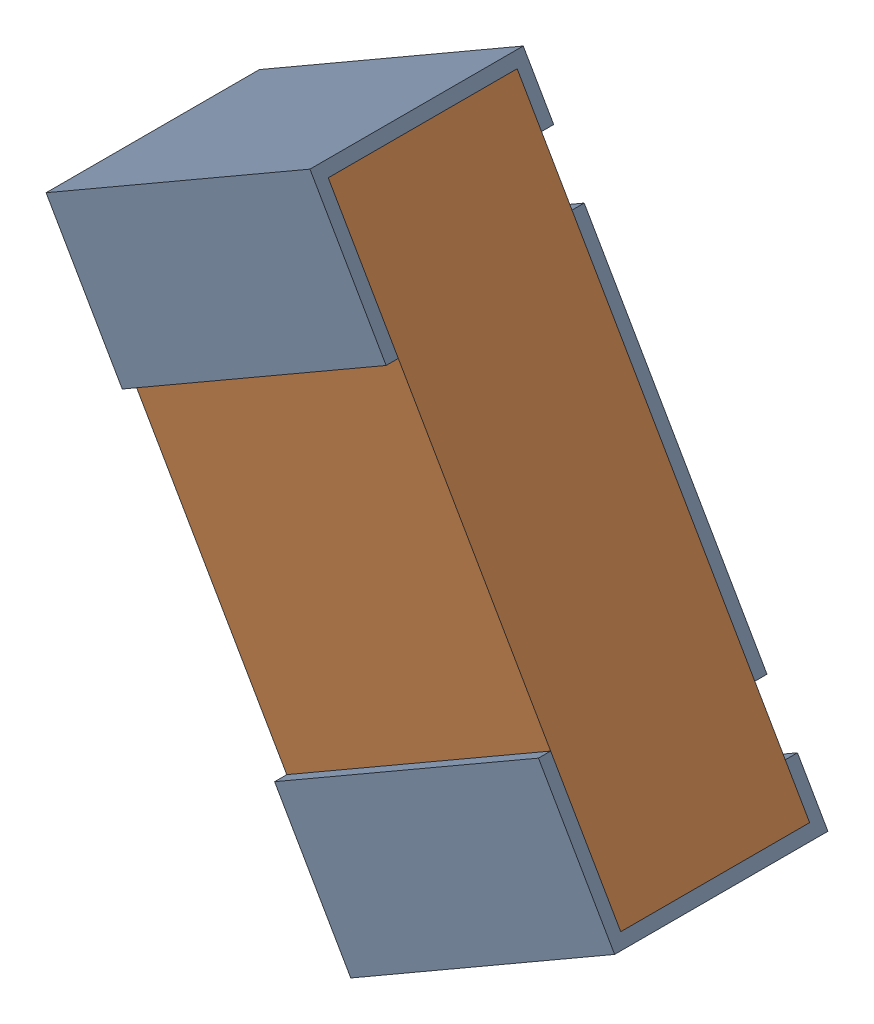
SolidWorks assembly R12, configuration Default. Lengths in mm.
Overall size (0.93 1.12 0.35).
3 component instances, 2 part files, 0 mates.
Components (placement in the parent):
- R12-subassembly-1-1: R12-subassembly-1 [Default] at (-5.679 -1.6229 -1.6307) x (0.5 -0.866025 0) z (0.866025 0.5 0) size (1 0.35 0.5)
  - 0402 resistor-1: 0402 resistor [Default] at origin size (1 0.35 0.5)
  - 0402 resistor-1-1: 0402 resistor-1 [Default] at origin size (0.96 0.31 0.5)
